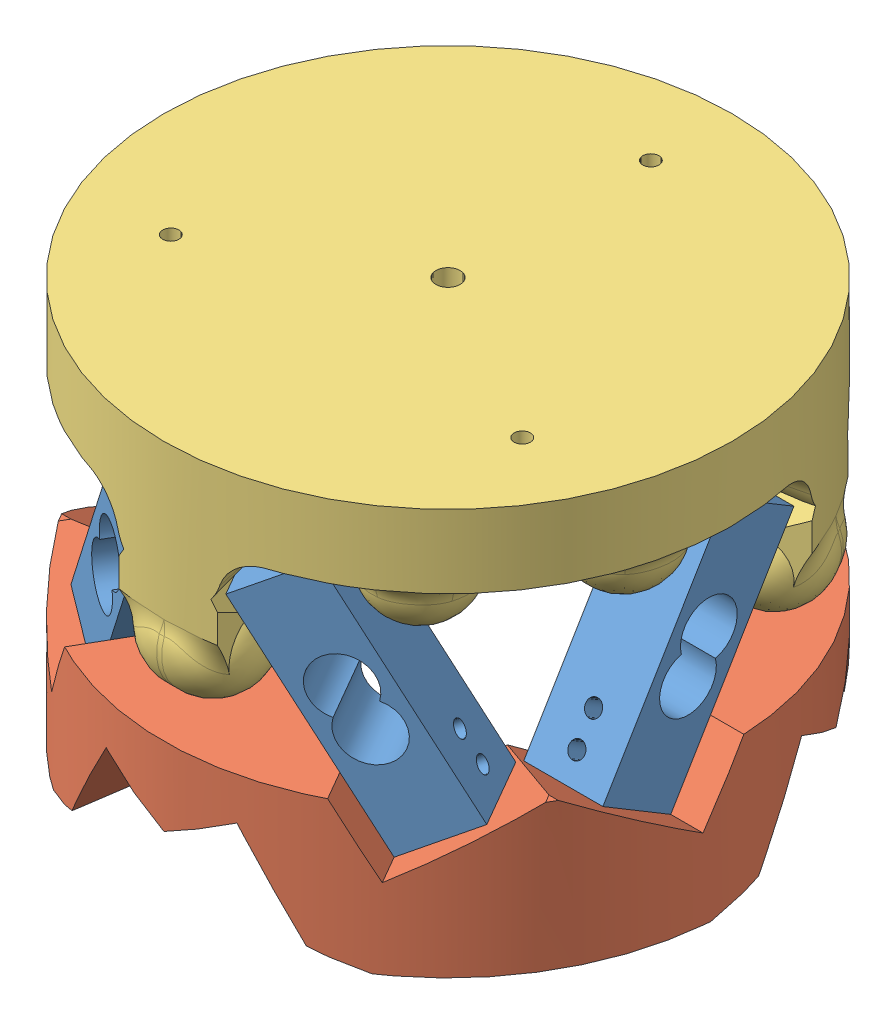
SolidWorks assembly Capteur 6 axes, configuration Défaut. Lengths in mm.
Overall size (140 100 141.21).
8 component instances, 3 part files, 18 mates.
Components (placement in the parent):
- Cellule_2kg-1: Cellule_2kg [Défaut] at (51.9615 50 0) x (1 0 0) z (0 -0.857493 0.514496) size (19.5 19.5 59)
- Cellule_2kg-2: Cellule_2kg [Défaut] at (25.9808 50 -45) x (0.5 0 -0.866025) z (0.445566 0.857493 0.257248) size (19.5 19.5 59)
- Cellule_2kg-3: Cellule_2kg [Défaut] at (-25.9808 50 -45) x (0.5 0 0.866025) z (-0.445566 0.857493 0.257248) size (19.5 19.5 59)
- Cellule_2kg-4: Cellule_2kg [Défaut] at (-51.9615 50 0) x (1 0 0) z (0 -0.857493 0.514496) size (19.5 19.5 59)
- Cellule_2kg-5: Cellule_2kg [Défaut] at (-25.9808 50 45) x (0.5 0 -0.866025) z (0.445566 0.857493 0.257248) size (19.5 19.5 59)
- Cellule_2kg-6: Cellule_2kg [Défaut] at (25.9808 50 45) x (0.5 0 0.866025) z (-0.445566 0.857493 0.257248) size (19.5 19.5 59)
- Bâti^Capteur 6 axes-1: Bâti^Capteur 6 axes [Défaut] at origin size (140 36 140) (virtual)
- Socle^Capteur 6 axes-1: Socle^Capteur 6 axes [Défaut] at origin size (140 56.9 141.21) (virtual)
Mates (geometry in assembly coordinates):
- Coïncidente1: coincident anti-aligned: line of Cellule_2kg-1 through (51.9615 77.8256 -16.6954) axis (0 -0.857493 0.514496); line of assembly
- Coïncidente2: coincident: point of Cellule_2kg-1; plane of assembly
- Coïncidente3: coincident anti-aligned: line of Cellule_2kg-2 through (11.5221 22.1744 -53.3477) axis (0.445566 0.857493 0.257248); line of assembly
- Coïncidente4: coincident: point of Cellule_2kg-2; plane of assembly
- Coïncidente5: coincident aligned: line of Cellule_2kg-3 through (-11.5221 22.1744 -53.3477) axis (-0.445566 0.857493 0.257248); line of assembly
- Coïncidente6: coincident: point of Cellule_2kg-3; plane of assembly
- Coïncidente7: coincident aligned: line of Cellule_2kg-4 through (-51.9615 77.8256 -16.6954) axis (0 -0.857493 0.514496); line of assembly
- Coïncidente8: coincident: point of Cellule_2kg-4; plane of assembly
- Coïncidente9: coincident aligned: line of Cellule_2kg-5 through (-40.4394 22.1744 36.6523) axis (0.445566 0.857493 0.257248); line of assembly
- Coïncidente10: coincident: point of Cellule_2kg-5; plane of assembly
- Coïncidente11: coincident anti-aligned: line of Cellule_2kg-6 through (40.4394 22.1744 36.6523) axis (-0.445566 0.857493 0.257248); line of assembly
- Coïncidente12: coincident: point of Cellule_2kg-6; plane of assembly
- Coïncidente15: coincident: line of Cellule_2kg-1 through (62.6865 50 0) axis (-1 0 0); point of assembly
- Coïncidente16: coincident: line of Cellule_2kg-2 through (31.3433 50 -54.2881) axis (-0.5 0 0.866025); point of assembly
- Coïncidente17: coincident: line of Cellule_2kg-3 through (-20.6183 50 -35.7119) axis (-0.5 0 -0.866025); point of assembly
- Coïncidente18: coincident: line of Cellule_2kg-4 through (-41.2365 50 0) axis (-1 0 0); point of assembly
- Coïncidente19: coincident: line of Cellule_2kg-5 through (-20.6183 50 35.7119) axis (-0.5 0 0.866025); point of assembly
- Coïncidente20: coincident: line of Cellule_2kg-6 through (31.3433 50 54.2881) axis (-0.5 0 -0.866025); point of assembly
